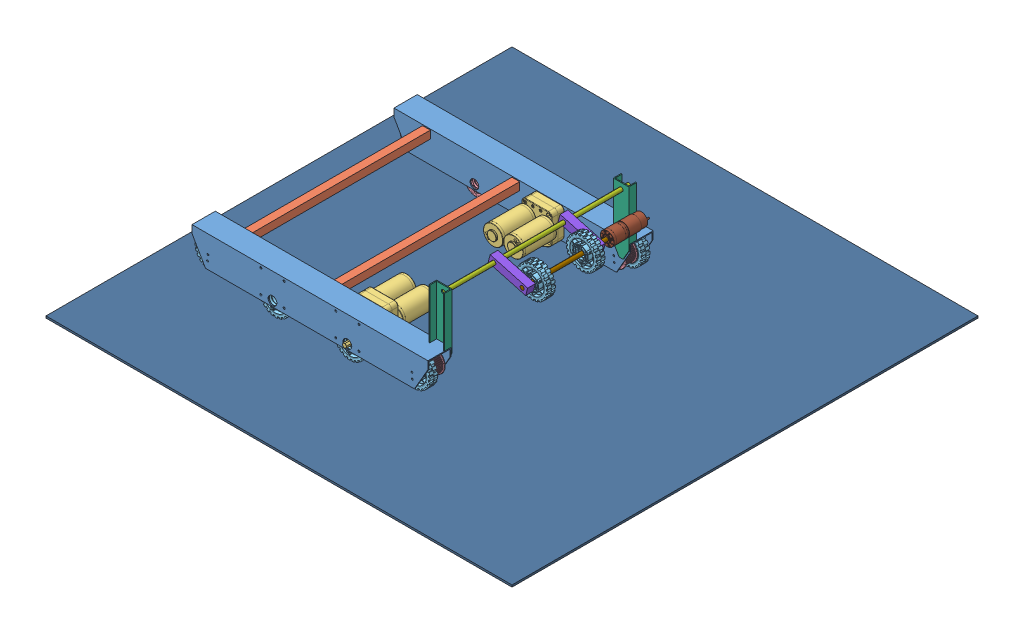
SolidWorks assembly 2016 Chassis, configuration Default. Lengths in mm.
Overall size (1524 326.16 1524).
40 component instances, 11 part files, 58 mates.
Components (placement in the parent):
- 3x4x31_C_channel-4: 3x4x31_C_channel [Right C Channel] at (-182.1989 -17.6287 955.5072) x (1 0.000001 0) z (0 0 1) size (771.41 101.6 76.2)
- 3x4x31_C_channel-8: 3x4x31_C_channel [Left C Channel] at (-182.1989 -17.6287 1615.9072) x (1 0.000001 0) z (0 0 1) size (771.41 101.6 76.2)
- 1x1_extrusion-1: 1x1_extrusion [Default] at (-461.599 17.296 1285.7072) x (1 0.000001 0) z (0 0 1) size (25.4 25.4 730.25)
- 1x1_extrusion-2: 1x1_extrusion [Default] at (-169.499 17.2963 1285.7072) x (1 0.000001 0) z (0 0 1) size (25.4 25.4 730.25)
- Gearbox-1: Gearbox [Default] at (-59.6931 -16.5942 1557.1697) x (1 -0.000149 0) z (0 0 1) size (141.64 114.27 241.64)
- Gearbox-2: Gearbox [Default] at (-59.6931 -16.6056 1014.2447) x (-1 0.000149 0) z (0 0 -1) size (141.64 114.27 241.64)
- Wheel_Pulley_Asm-1: Wheel_Pulley_Asm [Default] at (-72.5512 -120.0078 1626.5545) x (0 0 -1) z (0.609329 0.792917 0) size (68.56 101.6 101.6)
  - Double_Wide_Pulley-1: Double_Wide_Pulley [Default] at (-18.9345 -2.473 5.088) size (37.95 74.23 74.23)
  - 4 in HiGrip Wheel-1: 4 in HiGrip Wheel [Default] at (1.9518 29.3543 60.0417) x (1 0 0) z (0 0.000042 1) size (35.12 101.6 101.6)
- Wheel_Pulley_Asm-2: Wheel_Pulley_Asm [Default] at (-326.0645 -117.8653 1626.5545) x (0 0 -1) z (0.703485 0.71071 0) size (68.56 101.6 101.6)
  - Double_Wide_Pulley-1: Double_Wide_Pulley [Default] at (-18.9345 -2.473 5.088) size (37.95 74.23 74.23)
  - 4 in HiGrip Wheel-1: 4 in HiGrip Wheel [Default] at (1.9518 29.3543 60.0417) x (1 0 0) z (0 0.000042 1) size (35.12 101.6 101.6)
- Wheel_Pulley_Asm-3: Wheel_Pulley_Asm [Default] at (-578.2506 -57.4445 1626.5545) x (0 0 -1) z (1 0 0) size (68.56 101.6 101.6)
  - Double_Wide_Pulley-1: Double_Wide_Pulley [Default] at (-18.9345 -2.473 5.088) size (37.95 74.23 74.23)
  - 4 in HiGrip Wheel-1: 4 in HiGrip Wheel [Default] at (1.9518 29.3543 60.0417) x (1 0 0) z (0 0.000042 1) size (35.12 101.6 101.6)
- Wheel_Pulley_Asm-4: Wheel_Pulley_Asm [Default] at (88.7011 -57.4438 1626.5545) x (0 0 -1) z (1 0 0) size (68.56 101.6 101.6)
  - Double_Wide_Pulley-1: Double_Wide_Pulley [Default] at (-18.9345 -2.473 5.088) size (37.95 74.23 74.23)
  - 4 in HiGrip Wheel-1: 4 in HiGrip Wheel [Default] at (1.9518 29.3543 60.0417) x (1 0 0) z (0 0.000042 1) size (35.12 101.6 101.6)
- Wheel_Pulley_Asm-5: Wheel_Pulley_Asm [Default] at (2.8774 -82.844 944.8598) x (0 0 1) z (-1 0 0) size (68.56 101.6 101.6)
  - Double_Wide_Pulley-1: Double_Wide_Pulley [Default] at (-18.9345 -2.473 5.088) size (37.95 74.23 74.23)
  - 4 in HiGrip Wheel-1: 4 in HiGrip Wheel [Default] at (1.9518 29.3543 60.0417) x (1 0 0) z (0 0.000042 1) size (35.12 101.6 101.6)
- Wheel_Pulley_Asm-6: Wheel_Pulley_Asm [Default] at (-242.1234 -82.8443 944.8598) x (0 0 1) z (-1 0 0) size (68.56 101.6 101.6)
  - Double_Wide_Pulley-1: Double_Wide_Pulley [Default] at (-18.9345 -2.473 5.088) size (37.95 74.23 74.23)
  - 4 in HiGrip Wheel-1: 4 in HiGrip Wheel [Default] at (1.9518 29.3543 60.0417) x (1 0 0) z (0 0.000042 1) size (35.12 101.6 101.6)
- Wheel_Pulley_Asm-7: Wheel_Pulley_Asm [Default] at (213.8528 -57.4438 944.8598) x (0 0 1) z (-1 0 0) size (68.56 101.6 101.6)
  - Double_Wide_Pulley-1: Double_Wide_Pulley [Default] at (-18.9345 -2.473 5.088) size (37.95 74.23 74.23)
  - 4 in HiGrip Wheel-1: 4 in HiGrip Wheel [Default] at (1.9518 29.3543 60.0417) x (1 0 0) z (0 0.000042 1) size (35.12 101.6 101.6)
- Wheel_Pulley_Asm-8: Wheel_Pulley_Asm [Default] at (-453.0989 -57.4445 944.8598) x (0 0 1) z (-1 0 0) size (68.56 101.6 101.6)
  - Double_Wide_Pulley-1: Double_Wide_Pulley [Default] at (-18.9345 -2.473 5.088) size (37.95 74.23 74.23)
  - 4 in HiGrip Wheel-1: 4 in HiGrip Wheel [Default] at (1.9518 29.3543 60.0417) x (1 0 0) z (0 0.000042 1) size (35.12 101.6 101.6)
- 3580311-1: 3580311 [Default] at (178.1067 89.5597 1595.5872) x (0 0 1) z (-1 -0.000001 0) size (25.4 214.38 50.8)
- 3580311-2: 3580311 [Default] at (178.1067 89.5597 975.8272) x (0 0 -1) z (1 0.000001 0) size (25.4 214.38 50.8)
- 3580312-1: 3580312 [Default] at (178.1066 177.6977 1273.0072) x (1 0 0) z (0 1 0) size (12.7 603.25 12.7)
- 3580313-1: 3580313 [Default] at (223.9218 165.2037 1400.0072) x (0.263095 0.96477 0) z (0 0 1) size (25.4 127 25.4)
- 3580313-2: 3580313 [Default] at (223.9218 165.2037 1171.4072) x (0.263095 0.96477 0) z (0 0 1) size (25.4 127 25.4)
- 3580314-1: 3580314 [Default] at (270.3386 152.5458 1260.3072) x (1 0 0) z (0 -1 0) size (12.7 304.8 12.7)
- 4 in HiGrip Wheel-1: 4 in HiGrip Wheel [Default] at (272.8729 150.0222 1374.7213) x (0 0 1) z (-1 0 0) size (35.12 101.6 101.6)
- 4 in HiGrip Wheel-2: 4 in HiGrip Wheel [Default] at (272.8729 150.0222 1212.7963) x (0 0 1) z (-1 0 0) size (35.12 101.6 101.6)
- 358015-1: 358015 [Default] at (79.0133 -104.8775 1254.4438) x (1 0.000001 0) z (0 0 1) size (1524 6.35 1524)
- 3580315-1: 3580315 [Default] at (270.3386 152.5458 1022.8668) x (0 0 1) z (-0.923728 -0.383049 0) size (148.42 45 45)
Mates (geometry in assembly coordinates):
- Concentric3: concentric: cylinder of 3x4x31_C_channel-4 through (-461.599 17.296 851.8752) axis (0 0 1) radius 2.0828; cylinder of 1x1_extrusion-1 through (-461.599 17.296 838.5402) axis (0 0 1) radius 2.0828
- Coincident2: coincident anti-aligned: plane of 3x4x31_C_channel-4 through (203.5068 29.9967 990.4322) normal (0.000001 -1 0); plane of 1x1_extrusion-1 through (-474.299 29.9959 1650.8322) normal (-0.000001 1 0)
- Concentric4: concentric: cylinder of 3x4x31_C_channel-8 through (-461.599 17.296 1512.2752) axis (0 0 1) radius 2.0828; cylinder of 1x1_extrusion-1 through (-461.599 17.296 838.5402) axis (0 0 1) radius 2.0828
- Coincident3: coincident anti-aligned: plane of 3x4x31_C_channel-8 through (203.5068 29.9967 1650.8322) normal (0 0 -1); plane of 1x1_extrusion-1 through (-461.599 17.296 1650.8322) normal (0 0 1)
- Coincident4: coincident anti-aligned: plane of 3x4x31_C_channel-8 through (203.5068 29.9967 1650.8322) normal (0.000001 -1 0); plane of 1x1_extrusion-1 through (-474.299 29.9959 1650.8322) normal (-0.000001 1 0)
- Concentric5: concentric: cylinder of 3x4x31_C_channel-8 through (-169.499 17.2963 1512.2752) axis (0 0 1) radius 2.0828; cylinder of 1x1_extrusion-2 through (-169.499 17.2963 838.5402) axis (0 0 1) radius 2.0828
- Coincident5: coincident anti-aligned: plane of 3x4x31_C_channel-8 through (203.5068 29.9967 1650.8322) normal (0 0 -1); plane of 1x1_extrusion-2 through (-169.499 17.2963 1650.8322) normal (0 0 1)
- Coincident6: coincident anti-aligned: plane of 3x4x31_C_channel-8 through (203.5068 29.9967 1650.8322) normal (0.000001 -1 0); plane of 1x1_extrusion-2 through (-182.199 29.9963 1650.8322) normal (-0.000001 1 0)
- Concentric6: concentric: cylinder of 3x4x31_C_channel-4 through (-461.599 17.296 851.8752) axis (0 0 1) radius 2.0828; cylinder of 1x1_extrusion-1 through (-461.599 17.296 838.5402) axis (0 0 1) radius 2.0828
- Concentric7: concentric: cylinder of 3x4x31_C_channel-4 through (-169.499 17.2963 851.8752) axis (0 0 1) radius 2.0828; cylinder of 1x1_extrusion-2 through (-169.499 17.2963 838.5402) axis (0 0 1) radius 2.0828
- Coincident9: coincident anti-aligned: plane of 3x4x31_C_channel-4 through (203.5068 29.9967 920.5822) normal (0 0 1); plane of 1x1_extrusion-1 through (-461.599 17.296 920.5822) normal (0 0 -1)
- Coincident8: coincident anti-aligned: plane of 3x4x31_C_channel-4 through (203.5068 29.9967 920.5822) normal (0 0 1); plane of 1x1_extrusion-2 through (-169.499 17.2963 920.5822) normal (0 0 -1)
- Coincident10: coincident anti-aligned: plane of 3x4x31_C_channel-4 through (203.5068 29.9967 990.4322) normal (0.000001 -1 0); plane of 1x1_extrusion-1 through (-474.299 29.9959 1650.8322) normal (-0.000001 1 0)
- Coincident11: coincident anti-aligned: plane of 3x4x31_C_channel-4 through (203.5068 29.9967 990.4322) normal (0.000001 -1 0); plane of 1x1_extrusion-2 through (-182.199 29.9963 1650.8322) normal (-0.000001 1 0)
- Coincident13: coincident anti-aligned: plane of 3x4x31_C_channel-4 through (203.5068 33.1717 993.6072) normal (0 0 1); plane of Gearbox-2 through (-90.1781 -50.0665 993.6072) normal (0 0 -1)
- Distance1: distance = 0.7153 mm anti-aligned: plane of 3x4x31_C_channel-8 through (203.5068 29.9967 1650.8322) normal (0 0 -1); plane of Wheel_Pulley_Asm-1/4 in HiGrip Wheel-1 through (-59.6985 -50.9661 1650.1169) normal (0 0 1)
- Concentric13: concentric anti-aligned: cylinder of 3x4x31_C_channel-8 through (-304.6993 -50.9664 1512.2752) axis (0 0 1) radius 14.2875; cylinder of Wheel_Pulley_Asm-2/4 in HiGrip Wheel-1 through (-304.6993 -50.9664 1650.1169) axis (0 0 -1) radius 12.2174
- Distance2: distance = 0.7153 mm anti-aligned: plane of Wheel_Pulley_Asm-2/4 in HiGrip Wheel-1 through (-304.6993 -50.9664 1650.1169) normal (0 0 1); plane of 3x4x31_C_channel-8 through (203.5068 29.9967 1650.8322) normal (0 0 -1)
- Concentric14: concentric anti-aligned: cylinder of 3x4x31_C_channel-8 through (-515.6747 -25.5666 1512.2752) axis (0 0 1) radius 2.75; cylinder of Wheel_Pulley_Asm-3/4 in HiGrip Wheel-1 through (-515.6747 -25.5666 1650.1169) axis (0 0 -1) radius 12.2174
- Distance3: distance = 0.7153 mm anti-aligned: plane of Wheel_Pulley_Asm-3/4 in HiGrip Wheel-1 through (-515.6747 -25.5666 1650.1169) normal (0 0 1); plane of 3x4x31_C_channel-8 through (203.5068 29.9967 1650.8322) normal (0 0 -1)
- Concentric15: concentric aligned: cylinder of 3x4x31_C_channel-8 through (-59.6985 -50.9661 1512.2752) axis (0 0 1) radius 14.2875; cylinder of Wheel_Pulley_Asm-1/4 in HiGrip Wheel-1 through (-59.6985 -50.9661 1643.1319) axis (0 0 1) radius 14.2875
- Coincident17: coincident anti-aligned: plane of 3x4x31_C_channel-8 through (203.5068 33.1717 1577.8072) normal (0 0 -1); plane of Gearbox-1 through (-29.2181 -50.0641 1577.8072) normal (0 0 1)
- Concentric19: concentric anti-aligned: cylinder of 3x4x31_C_channel-8 through (151.2769 -25.5659 1512.2752) axis (0 0 1) radius 2.75; cylinder of Wheel_Pulley_Asm-4/4 in HiGrip Wheel-1 through (151.2769 -25.5659 1650.1169) axis (0 0 -1) radius 12.2174
- Distance4: distance = 0.7153 mm anti-aligned: plane of Wheel_Pulley_Asm-4/4 in HiGrip Wheel-1 through (151.2769 -25.5659 1650.1169) normal (0 0 1); plane of 3x4x31_C_channel-8 through (203.5068 29.9967 1650.8322) normal (0 0 -1)
- Concentric20: concentric aligned: cylinder of 3x4x31_C_channel-4 through (-59.6985 -50.9661 851.8752) axis (0 0 1) radius 14.2875; cylinder of Wheel_Pulley_Asm-5/4 in HiGrip Wheel-1 through (-59.6985 -50.9661 921.2974) axis (0 0 1) radius 12.2174
- Distance5: distance = 0.7153 mm anti-aligned: plane of Wheel_Pulley_Asm-5/4 in HiGrip Wheel-1 through (-59.6985 -50.9661 921.2974) normal (0 0 -1); plane of 3x4x31_C_channel-4 through (203.5068 29.9967 920.5822) normal (0 0 1)
- Concentric21: concentric aligned: cylinder of 3x4x31_C_channel-4 through (-304.6993 -50.9664 851.8752) axis (0 0 1) radius 14.2875; cylinder of Wheel_Pulley_Asm-6/4 in HiGrip Wheel-1 through (-304.6993 -50.9664 921.2974) axis (0 0 1) radius 12.2174
- Distance6: distance = 0.7153 mm anti-aligned: plane of Wheel_Pulley_Asm-6/4 in HiGrip Wheel-1 through (-304.6993 -50.9664 921.2974) normal (0 0 -1); plane of 3x4x31_C_channel-4 through (203.5068 29.9967 920.5822) normal (0 0 1)
- Concentric22: concentric aligned: cylinder of 3x4x31_C_channel-4 through (151.2769 -25.5659 851.8752) axis (0 0 1) radius 2.75; cylinder of Wheel_Pulley_Asm-7/4 in HiGrip Wheel-1 through (151.2769 -25.5659 921.2974) axis (0 0 1) radius 12.2174
- Distance7: distance = 0.7153 mm anti-aligned: plane of Wheel_Pulley_Asm-7/4 in HiGrip Wheel-1 through (151.2769 -25.5659 921.2974) normal (0 0 -1); plane of 3x4x31_C_channel-4 through (203.5068 29.9967 920.5822) normal (0 0 1)
- Concentric23: concentric aligned: cylinder of 3x4x31_C_channel-4 through (-515.6747 -25.5666 851.8752) axis (0 0 1) radius 2.75; cylinder of Wheel_Pulley_Asm-8/4 in HiGrip Wheel-1 through (-515.6747 -25.5666 921.2974) axis (0 0 1) radius 12.2174
- Distance8: distance = 0.7153 mm anti-aligned: plane of Wheel_Pulley_Asm-8/4 in HiGrip Wheel-1 through (-515.6747 -25.5666 921.2974) normal (0 0 -1); plane of 3x4x31_C_channel-4 through (203.5068 29.9967 920.5822) normal (0 0 1)
- Concentric24: concentric aligned: cylinder of 3x4x31_C_channel-8 through (-21.5871 23.448 1654.0072) axis (0 0 -1) radius 3.302; cylinder of Gearbox-1 through (-21.5871 23.448 1545.4222) axis (0 0 -1) radius 2.5146
- Concentric25: concentric aligned: cylinder of 3x4x31_C_channel-8 through (-21.5985 -52.752 1654.0072) axis (0 0 -1) radius 3.302; cylinder of Gearbox-1 through (-21.5985 -52.752 1545.4222) axis (0 0 -1) radius 2.5146
- Concentric26: concentric aligned: cylinder of 3x4x31_C_channel-4 through (-97.7871 23.4479 960.3635) axis (0 0 1) radius 3.302; cylinder of Gearbox-2 through (-97.7871 23.4479 1025.9922) axis (0 0 1) radius 2.5146
- Concentric27: concentric aligned: cylinder of 3x4x31_C_channel-4 through (-97.7985 -52.7521 960.3635) axis (0 0 1) radius 3.302; cylinder of Gearbox-2 through (-97.7985 -52.7521 1025.9922) axis (0 0 1) radius 2.5146
- Coincident18: coincident anti-aligned: plane of 3x4x31_C_channel-8 through (203.5068 33.1717 1577.8072) normal (0 0 -1); plane of 3580311-1 through (200.3316 196.7477 1577.8072) normal (0 0 1)
- Coincident19: coincident anti-aligned: plane of 3x4x31_C_channel-8 through (203.5068 33.1717 1654.0072) normal (-0.000001 1 0); plane of 3580311-1 through (360.7328 33.1718 1577.8072) normal (0.000001 -1 0)
- Distance9: distance = 0 mm aligned: plane of 3580311-1 through (203.5066 196.7477 1574.6322) normal (1 0.000001 0); plane of 3x4x31_C_channel-8 through (203.5068 -17.6283 1615.9072) normal (1 0.000001 0)
- Coincident21: coincident anti-aligned: plane of 3x4x31_C_channel-4 through (203.5068 33.1717 993.6072) normal (0 0 1); plane of 3580311-2 through (155.8816 196.7476 993.6072) normal (0 0 -1)
- Distance10: distance = 0 mm aligned: plane of 3580311-2 through (203.5066 196.7477 971.3822) normal (1 0.000001 0); plane of 3x4x31_C_channel-4 through (203.5068 -17.6283 955.5072) normal (1 0.000001 0)
- Coincident23: coincident anti-aligned: plane of 3x4x31_C_channel-4 through (203.5068 33.1717 993.6072) normal (-0.000001 1 0); plane of 3580311-2 through (-4.5192 33.1715 993.6072) normal (0.000001 -1 0)
- Concentric28: concentric anti-aligned: cylinder of 3580311-1 through (178.1066 177.6977 1620.6062) axis (0 0 -1) radius 6.35; cylinder of 3580312-1 through (178.1066 177.6977 971.3822) axis (0 0 1) radius 6.35
- Parallel1: parallel aligned: cylinder of 3580311-2 through (178.1066 177.6977 950.8082) axis (0 0 1) radius 6.35; cylinder of 3580312-1 through (178.1066 177.6977 971.3822) axis (0 0 1) radius 6.35
- Distance11: distance = 22.225 mm aligned: plane of 3580312-1 through (178.1066 177.6977 971.3822) normal (0 0 -1); plane of 3580311-2 through (155.8816 196.7476 993.6072) normal (0 0 -1)
- Concentric30: concentric aligned: cylinder of 3580312-1 through (178.1066 177.6977 971.3822) axis (0 0 1) radius 6.35; cylinder of 3580313-1 through (178.1066 177.6977 1285.7072) axis (0 0 1) radius 6.35
- Concentric31: concentric aligned: cylinder of 3580312-1 through (178.1066 177.6977 971.3822) axis (0 0 1) radius 6.35; cylinder of 3580313-2 through (178.1066 177.6977 1057.1072) axis (0 0 1) radius 6.35
- Distance12: distance = 203.2 mm anti-aligned: plane of 3580313-2 through (159.3177 169.6577 1184.1072) normal (0 0 1); plane of 3580313-1 through (159.3177 169.6577 1387.3072) normal (0 0 -1)
- Distance13: distance = 161.925 mm anti-aligned: plane of 3580311-1 through (178.1066 196.7477 1574.6322) normal (0 0 -1); plane of 3580313-1 through (159.3177 169.6577 1412.7072) normal (0 0 1)
- Concentric32: concentric anti-aligned: cylinder of 3580313-1 through (270.3386 152.5458 1285.7072) axis (0 0 1) radius 6.35; cylinder of 3580314-1 through (270.3386 152.5458 1412.7072) axis (0 0 -1) radius 6.35
- Coincident25: coincident aligned: plane of 3580313-1 through (159.3177 169.6577 1412.7072) normal (0 0 1); plane of 3580314-1 through (270.3386 152.5458 1412.7072) normal (0 0 1)
- Concentric33: concentric anti-aligned: cylinder of 3580314-1 through (270.3386 152.5458 1412.7072) axis (0 0 -1) radius 6.35; cylinder of 4 in HiGrip Wheel-1 through (270.3386 152.5458 1349.2072) axis (0 0 1) radius 12.2174
- Concentric34: concentric anti-aligned: cylinder of 3580313-2 through (270.3386 152.5458 1057.1072) axis (0 0 1) radius 6.35; cylinder of 3580314-1 through (270.3386 152.5458 1412.7072) axis (0 0 -1) radius 6.35
- Concentric35: concentric anti-aligned: cylinder of 3580314-1 through (270.3386 152.5458 1412.7072) axis (0 0 -1) radius 6.35; cylinder of 4 in HiGrip Wheel-2 through (270.3386 152.5458 1187.2822) axis (0 0 1) radius 12.2174
- Distance14: distance = 127 mm anti-aligned: plane of 4 in HiGrip Wheel-2 through (270.3386 152.5458 1222.2072) normal (0 0 1); plane of 4 in HiGrip Wheel-1 through (270.3386 152.5458 1349.2072) normal (0 0 -1)
- Distance15: distance = 3.175 mm anti-aligned: plane of 4 in HiGrip Wheel-1 through (270.3386 152.5458 1384.1322) normal (0 0 1); plane of 3580313-1 through (159.3177 169.6577 1387.3072) normal (0 0 -1)
- Distance16: distance = 134.874 mm aligned: plane of 3x4x31_C_channel-8 through (203.5068 33.1717 1654.0072) normal (-0.000001 1 0); plane of 358015-1 through (79.0133 -101.7025 1254.4438) normal (-0.000001 1 0)
- Concentric36: concentric aligned: cylinder of 3580314-1 through (270.3386 152.5458 1412.7072) axis (0 0 -1) radius 6.35; cylinder of 3580315-1 through (270.3386 152.5458 1161.7665) axis (0 0 -1) radius 5
